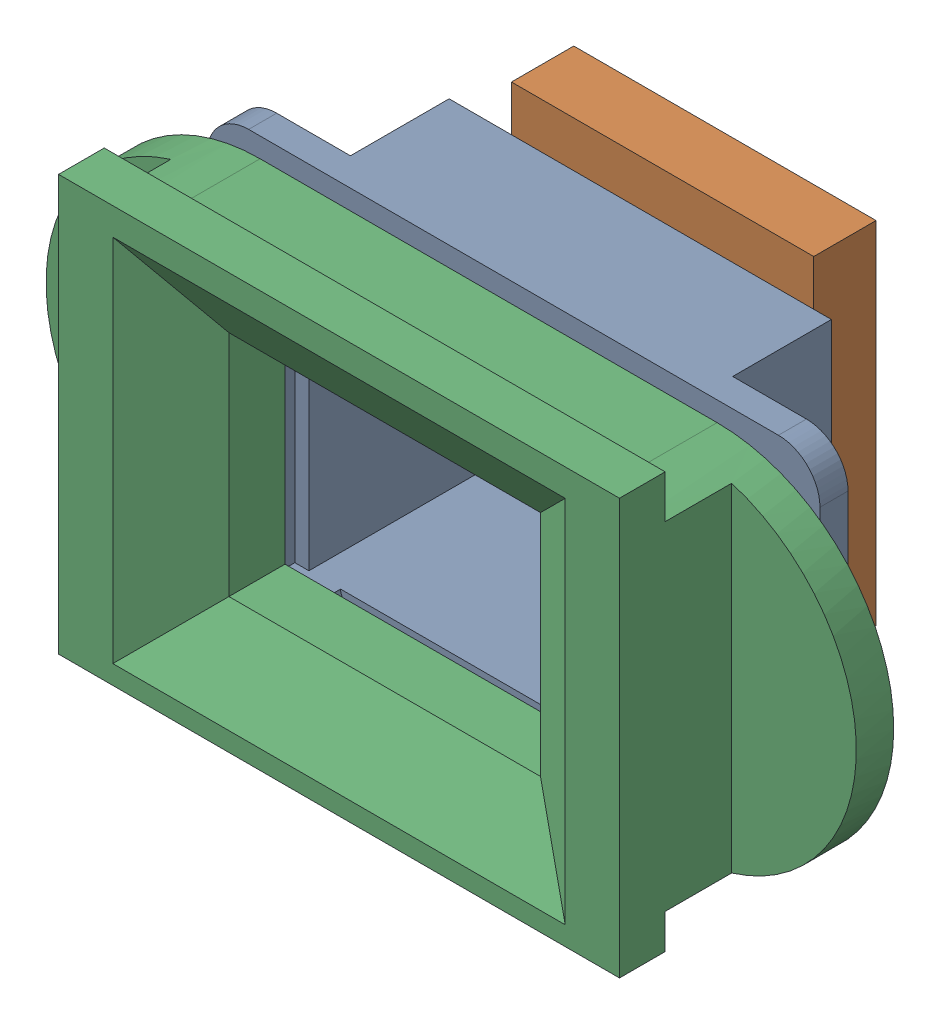
SolidWorks assembly _okular, configuration По умолчанию. Lengths in mm.
Overall size (39 20 18.3).
3 component instances, 3 part files, 6 mates.
Components (placement in the parent):
- _lensHolder-1: _lensHolder [По умолчанию] at origin size (29.5 16.75 9.4)
- _display-1: _display [По умолчанию] at (0.075 0.225 -5.75) size (14.55 16.9 4)
- _cover-1: _cover [По умолчанию] at (-0.2 -0.075 7.35) x (1 0 0) z (0 0 -1) size (39 20 7.2)
Mates (geometry in assembly coordinates):
- Совпадение1: coincident anti-aligned: plane of lensHolder-1 through (0 0 -4.75) normal (0 0 -1); plane of display-1 through (0.075 0.225 -4.75) normal (0 0 1)
- Совпадение3: coincident anti-aligned: plane of lensHolder-1 through (-7.35 6.075 -4.75) normal (0 -1 0); plane of display-1 through (-7.2 6.075 -4.75) normal (0 1 0)
- Совпадение4: coincident anti-aligned: plane of lensHolder-1 through (7.35 -6.075 -4.75) normal (-1 0 0); plane of display-1 through (7.35 -5.625 -4.75) normal (1 0 0)
- Совпадение5: coincident anti-aligned: plane of lensHolder-1 through (0 0 4.65) normal (0 0 1); plane of cover-1 through (-0.2 -0.075 4.65) normal (0 0 -1)
- Совпадение6: coincident anti-aligned: plane of lensHolder-1 through (-9.3 7.425 4.65) normal (0 1 0); plane of cover-1 through (-9.7 7.425 4.65) normal (0 -1 0)
- Совпадение7: coincident anti-aligned: plane of lensHolder-1 through (9.3 -7.425 4.65) normal (1 0 0); plane of cover-1 through (9.3 7.425 4.65) normal (-1 0 0)
